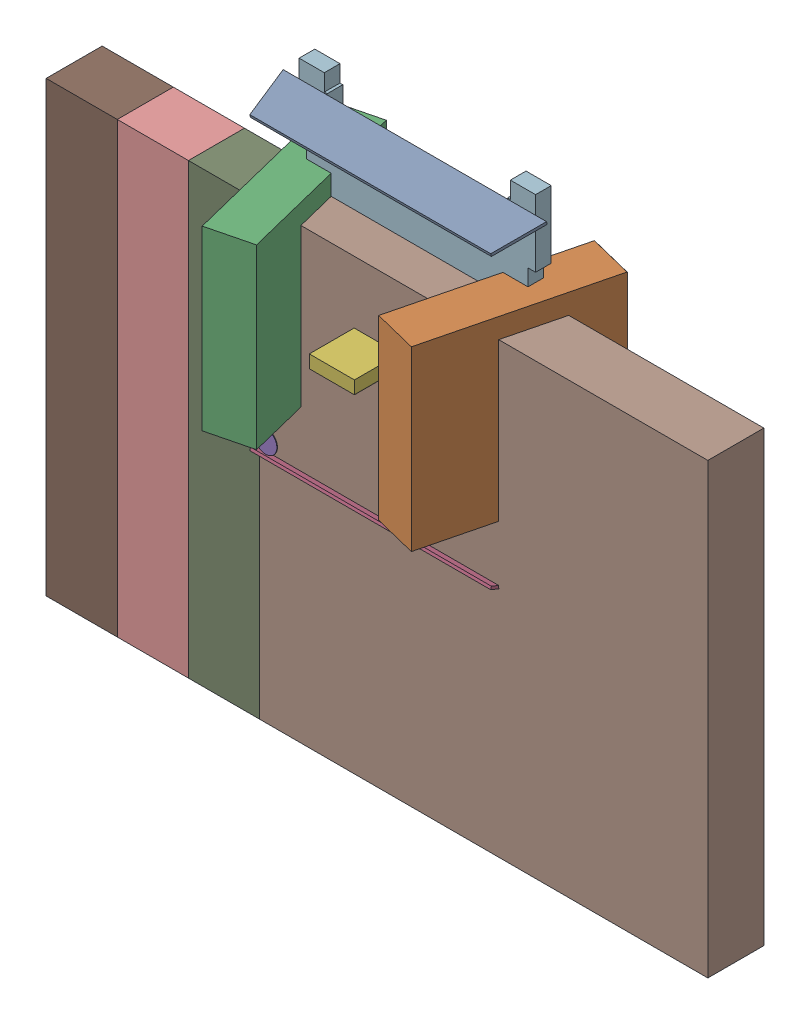
SolidWorks assembly User Library-DFN5x6_SO8FL, configuration ﾃﾞﾌｫﾙﾄ. Lengths in mm.
Overall size (11.81 9.85 3.29).
25 component instances, 7 part files, 0 mates.
Components (placement in the parent):
- Free-Models-1: Free-Models [ﾃﾞﾌｫﾙﾄ] at origin size (11.81 9.85 3.29)
  - SIDE_S-1: SIDE_S [ﾃﾞﾌｫﾙﾄ] at (1.9 5.4223 0.705) x (1 0 0) z (0 0.970296 0.241922) size (4.7 0.82 0.05)
    - Extruded-1: Extruded [ﾃﾞﾌｫﾙﾄ] at origin size (4.7 0.82 0.05)
  - SIDE_L-1: SIDE_L [ﾃﾞﾌｫﾙﾄ] at (4.1508 2.775 0.705) x (0.241922 0 -0.970296) z (-0.970296 0 -0.241922) size (3.19 3.17 0.81)
    - Extruded_2-1: Extruded_2 [ﾃﾞﾌｫﾙﾄ] at origin size (3.19 3.17 0.81)
  - SIDE_L-1-1: SIDE_L-1 [ﾃﾞﾌｫﾙﾄ] at (-0.3508 2.775 0.705) x (-0.241922 0 -0.970296) z (0.970296 0 -0.241922) size (3.19 3.17 0.81)
    - Extruded_2-1: Extruded_2 [ﾃﾞﾌｫﾙﾄ] at origin size (3.19 3.17 0.81)
  - SIDE_S-1-1: SIDE_S-1 [ﾃﾞﾌｫﾙﾄ] at (1.9 0.1277 0.705) x (-1 0 0) z (0 -0.970296 0.241922) size (4.7 0.82 0.05)
    - Extruded-1: Extruded [ﾃﾞﾌｫﾙﾄ] at origin size (4.7 0.82 0.05)
  - 587257496-1: 587257496 [ﾃﾞﾌｫﾙﾄ] at (0.0484 0.4796 1.12) size (0.4 0.4 0.01)
    - Cylinder-1: Cylinder [ﾃﾞﾌｫﾙﾄ] at origin size (0.4 0.4 0.01)
  - 750905040-1: 750905040 [ﾃﾞﾌｫﾙﾄ] at (1.9 2.775 1) size (0.8 0.23 0.8)
    - Extruded_3-1: Extruded_3 [ﾃﾞﾌｫﾙﾄ] at origin size (0.8 0.23 0.8)
  - 266863104-1: 266863104 [ﾃﾞﾌｫﾙﾄ] at (1.9025 2.775 0.02) size (0.8 1.14 0.8)
    - Extruded_4-1: Extruded_4 [ﾃﾞﾌｫﾙﾄ] at origin size (0.8 1.14 0.8)
  - 500156144-1: 500156144 [ﾃﾞﾌｫﾙﾄ] at (3.81 0 0) size (8 8 1)
    - Extruded_5-1: Extruded_5 [ﾃﾞﾌｫﾙﾄ] at origin size (8 8 1)
  - 500156144-1-1: 500156144-1 [ﾃﾞﾌｫﾙﾄ] at (2.54 0 0) size (8 8 1)
    - Extruded_5-1: Extruded_5 [ﾃﾞﾌｫﾙﾄ] at origin size (8 8 1)
  - 500156144-2-1: 500156144-2 [ﾃﾞﾌｫﾙﾄ] at (1.27 0 0) size (8 8 1)
    - Extruded_5-1: Extruded_5 [ﾃﾞﾌｫﾙﾄ] at origin size (8 8 1)
  - 500156144-3-1: 500156144-3 [ﾃﾞﾌｫﾙﾄ] at origin size (8 8 1)
    - Extruded_5-1: Extruded_5 [ﾃﾞﾌｫﾙﾄ] at origin size (8 8 1)
  - 500160368-1: 500160368 [ﾃﾞﾌｫﾙﾄ] at (1.905 3.335 0) size (5.15 5.03 0.28)
    - Extruded_6-1: Extruded_6 [ﾃﾞﾌｫﾙﾄ] at origin size (5.15 5.03 0.28)
